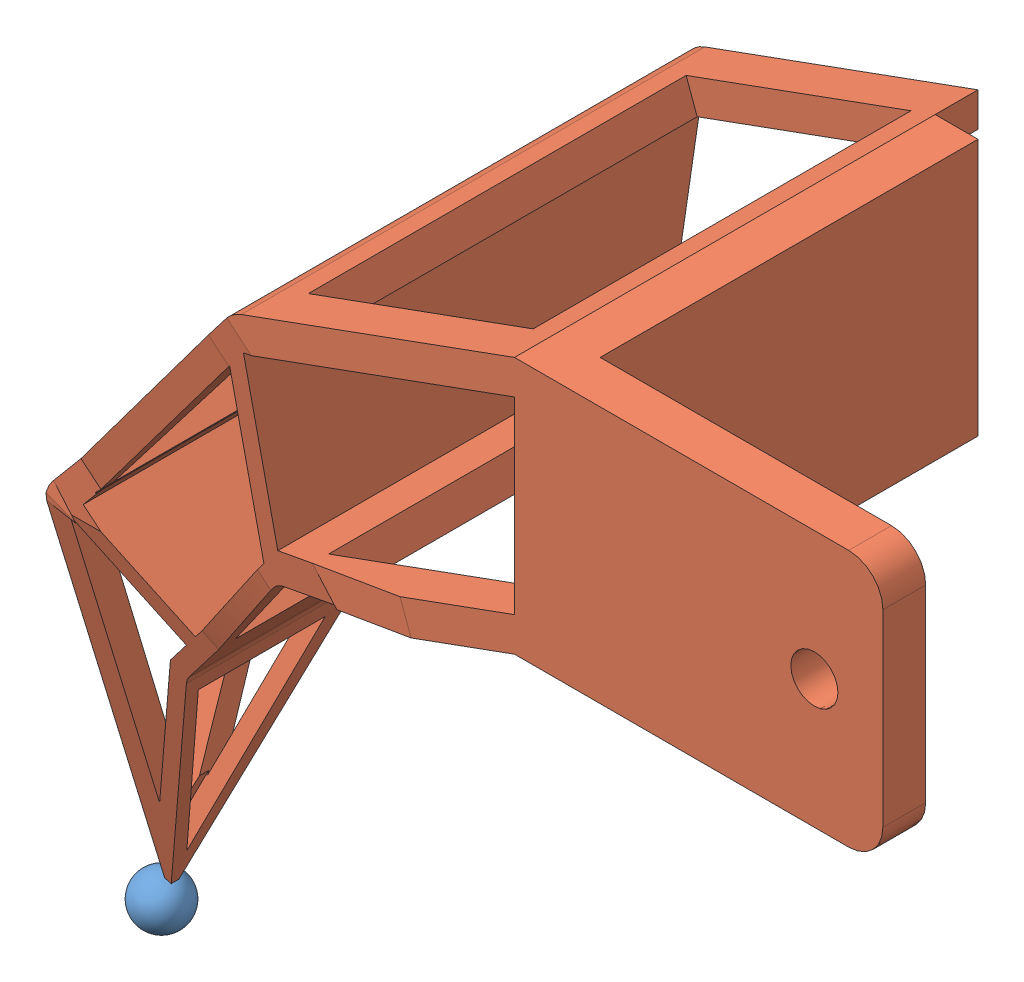
SolidWorks assembly 13, configuration Défaut. Lengths in mm.
Overall size (114.25 105.39 54.1).
2 component instances, 2 part files, 0 mates.
Components (placement in the parent):
- sphere2-1: sphere2 [Défaut] at (1.2052 0.3598 6) size (6 6 6)
- below hand2-2: below hand2 [Défaut] at (71.4508 72.7499 28.05) size (110.36 101.25 54.1)
